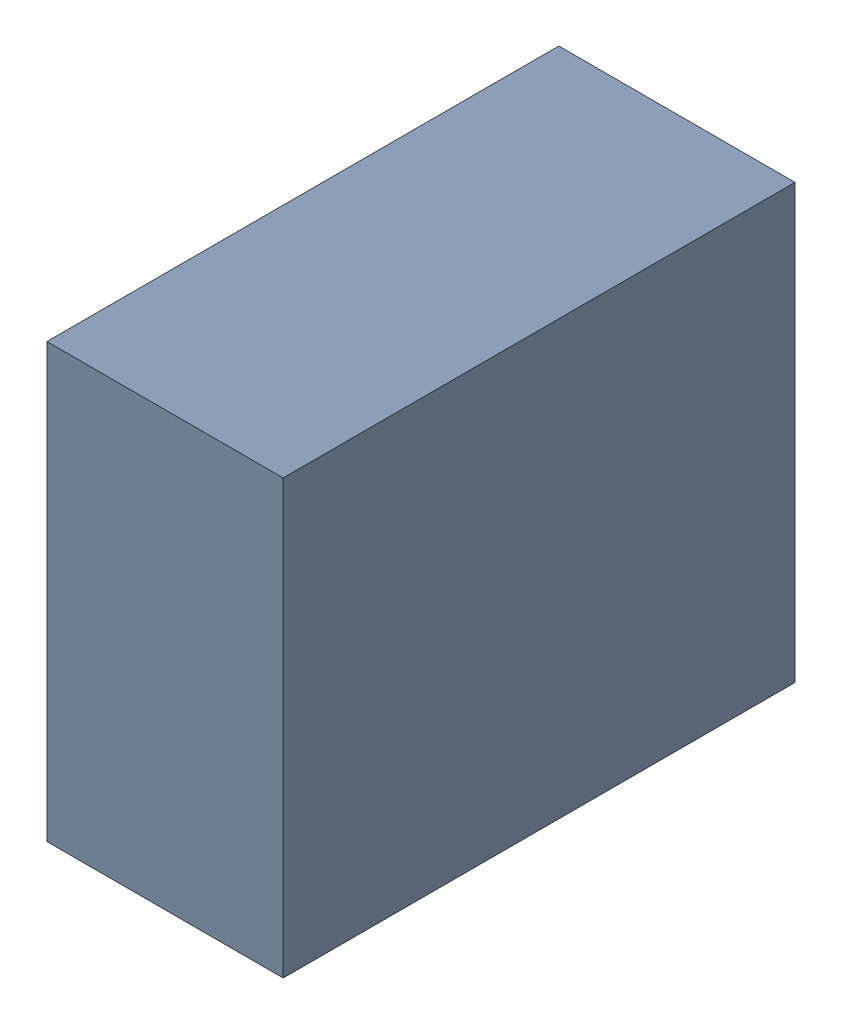
SolidWorks assembly C205, configuration Standard. Lengths in mm.
Overall size (0.6 1.1 1.3).
2 component instances, 1 part files, 0 mates.
Components (placement in the parent):
- 885542376-1: 885542376 [Standard] at (13.15 -17.5 0) size (0.6 1.1 1.3)
  - Extruded_25-1: Extruded_25 [Standard] at origin size (0.6 1.1 1.3)
